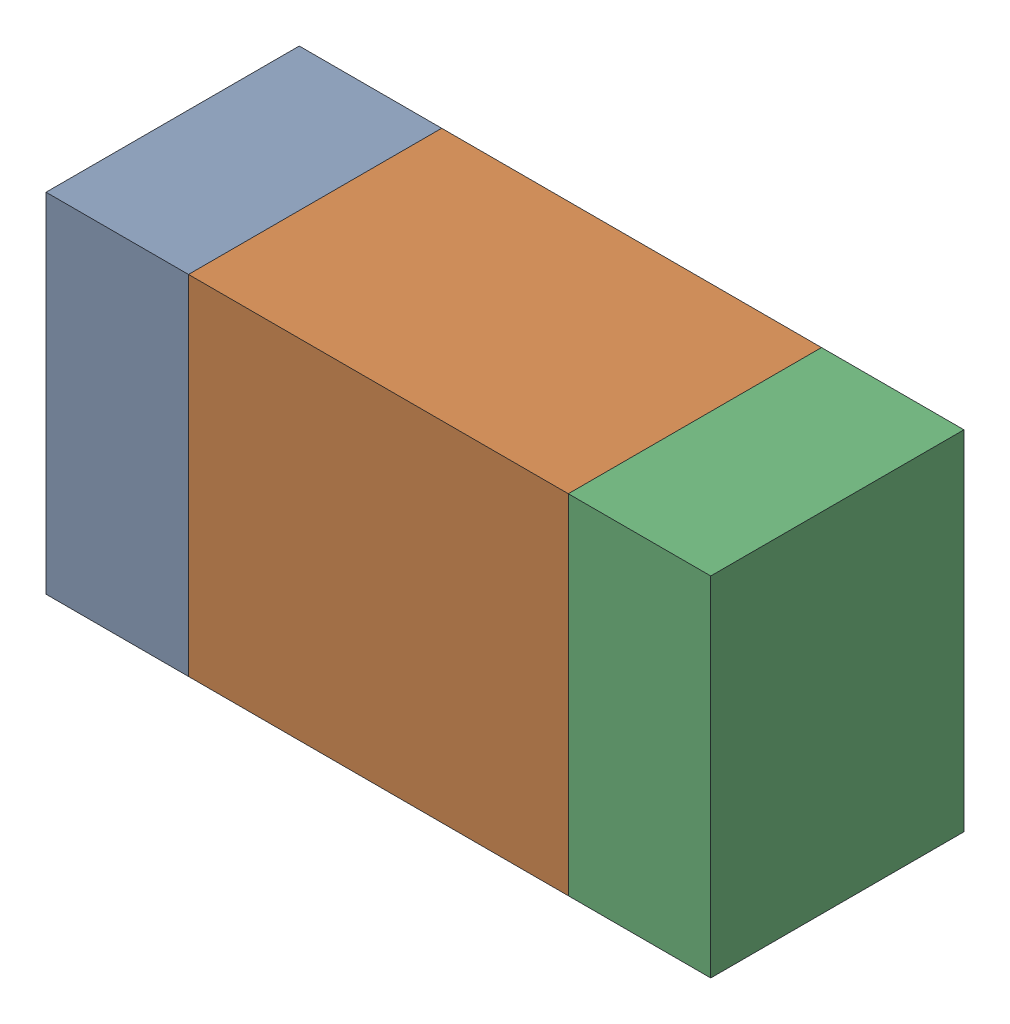
SolidWorks assembly R404PCB, configuration Default. Lengths in mm.
Overall size (1.05 0.55 0.4).
6 component instances, 2 part files, 0 mates.
Components (placement in the parent):
- 854785432-1: 854785432 [Default] at (88.1776 85.7001 0) size (0.22 0.55 0.4)
  - Extruded-1: Extruded [Default] at origin size (0.22 0.55 0.4)
- 854785568-1: 854785568 [Default] at (88.5901 85.7001 0) size (0.6 0.55 0.4)
  - Extruded_2-1: Extruded_2 [Default] at origin size (0.6 0.55 0.4)
- 854785432-2: 854785432 [Default] at (89.0026 85.7001 0) size (0.22 0.55 0.4)
  - Extruded-1: Extruded [Default] at origin size (0.22 0.55 0.4)
